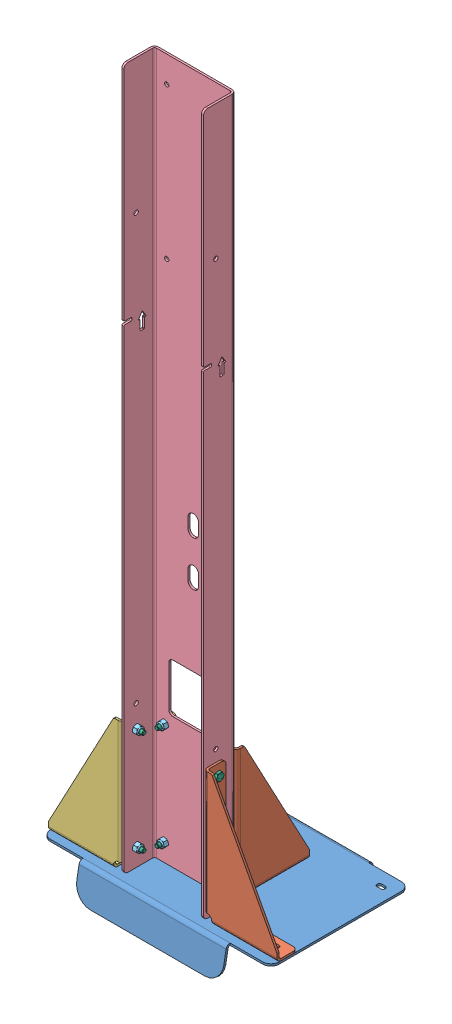
SolidWorks assembly GE-22383, configuration Default. Lengths in mm.
Overall size (355.6 1141.19 244.2).
34 component instances, 6 part files, 31 mates.
Components (placement in the parent):
- GE-22372-1: GE-22372 [Default] at (0 -3.175 0) x (-1 0 0) z (0 0 -1) size (355.6 50.58 244.2)
- GE-22373-1: GE-22373 [Default] at (63.5 3.175 95.25) x (0 1 0) z (0 0 -1) size (203.2 114.3 31.75)
- GE-22373-2: GE-22373 [Default] at (60.325 3.175 47.625) x (0 1 0) z (-1 0 0) size (203.2 114.3 31.75)
- GE-22374-1: GE-22374 [GE-22374] at (-60.325 3.175 47.625) x (0 1 0) z (-1 0 0) size (203.2 114.3 31.75)
- GE-22374-2: GE-22374 [GE-22374] at (-63.5 3.175 95.25) x (0 1 0) z (0 0 1) size (203.2 114.3 31.75)
- GE-22375-1: GE-22375 [Default] at (63.5 1106.4875 98.425) x (-1 0 0) z (0 0 1) size (127 1090.61 50.8)
- nylock_.25_20-2: nylock_.25_20 [Default] at (92.075 0 79.375) x (0.987919 0 -0.154972) z (-0.154972 0 -0.987919) size (11.11 7.94 12.83)
- hex_.25_20_0.75-2: hex_.25_20_0.75 [Default] at (92.075 -1.1906 79.375) x (0 -1 0) z (0.968106 0 -0.250542) size (23.02 12.83 11.11)
- hex_.25_20_0.75-3: hex_.25_20_0.75 [Default] at (59.1344 31.75 79.375) x (-1 0 0) z (0 -0.405813 -0.913956) size (23.02 12.83 11.11)
- hex_.25_20_0.75-4: hex_.25_20_0.75 [Default] at (-44.45 31.75 51.9906) x (0 0 1) z (-0.989795 -0.142496 0) size (23.02 12.83 11.11)
- nylock_.25_20-3: nylock_.25_20 [Default] at (60.325 31.75 79.375) x (0 -0.653939 0.756548) z (0 -0.756548 -0.653939) size (11.11 7.94 12.83)
- nylock_.25_20-4: nylock_.25_20 [Default] at (-44.45 31.75 50.8) x (0.219001 0.975725 0) z (0.975725 -0.219001 0) size (11.11 7.94 12.83)
- nylock_.25_20-5: nylock_.25_20 [Default] at (-92.075 0 79.375) x (0.987919 0 -0.154972) z (-0.154972 0 -0.987919) size (11.11 7.94 12.83)
- nylock_.25_20-6: nylock_.25_20 [Default] at (-44.45 0 -44.45) x (0.987919 0 -0.154972) z (-0.154972 0 -0.987919) size (11.11 7.94 12.83)
- nylock_.25_20-7: nylock_.25_20 [Default] at (44.45 0 -44.45) x (0.987919 0 -0.154972) z (-0.154972 0 -0.987919) size (11.11 7.94 12.83)
- nylock_.25_20-8: nylock_.25_20 [Default] at (-44.45 0 19.05) x (0.987919 0 -0.154972) z (-0.154972 0 -0.987919) size (11.11 7.94 12.83)
- nylock_.25_20-9: nylock_.25_20 [Default] at (44.45 0 19.05) x (0.987919 0 -0.154972) z (-0.154972 0 -0.987919) size (11.11 7.94 12.83)
- hex_.25_20_0.75-5: hex_.25_20_0.75 [Default] at (-92.075 -1.1906 79.375) x (0 -1 0) z (0.968106 0 -0.250542) size (23.02 12.83 11.11)
- hex_.25_20_0.75-6: hex_.25_20_0.75 [Default] at (-44.45 -1.1906 -44.45) x (0 -1 0) z (0.968106 0 -0.250542) size (23.02 12.83 11.11)
- hex_.25_20_0.75-7: hex_.25_20_0.75 [Default] at (44.45 -1.1906 -44.45) x (0 -1 0) z (0.968106 0 -0.250542) size (23.02 12.83 11.11)
- hex_.25_20_0.75-8: hex_.25_20_0.75 [Default] at (-44.45 -1.1906 19.05) x (0 -1 0) z (0.968106 0 -0.250542) size (23.02 12.83 11.11)
- hex_.25_20_0.75-9: hex_.25_20_0.75 [Default] at (44.45 -1.1906 19.05) x (0 -1 0) z (0.968106 0 -0.250542) size (23.02 12.83 11.11)
- nylock_.25_20-10: nylock_.25_20 [Default] at (60.325 190.5 79.375) x (0 -0.653939 0.756548) z (0 -0.756548 -0.653939) size (11.11 7.94 12.83)
- hex_.25_20_0.75-10: hex_.25_20_0.75 [Default] at (59.1344 190.5 79.375) x (-1 0 0) z (0 -0.405813 -0.913956) size (23.02 12.83 11.11)
- hex_.25_20_0.75-12: hex_.25_20_0.75 [Default] at (-59.1344 31.75 79.375) x (1 0 0) z (0 0.750375 0.661012) size (23.02 12.83 11.11)
- nylock_.25_20-12: nylock_.25_20 [Default] at (-60.325 31.75 79.375) x (0 -0.957606 -0.288082) z (0 -0.288082 0.957606) size (11.11 7.94 12.83)
- hex_.25_20_0.75-13: hex_.25_20_0.75 [Default] at (-59.1344 190.5 79.375) x (1 0 0) z (0 0.750375 0.661012) size (23.02 12.83 11.11)
- nylock_.25_20-13: nylock_.25_20 [Default] at (-60.325 190.5 79.375) x (0 -0.957606 -0.288082) z (0 -0.288082 0.957606) size (11.11 7.94 12.83)
- nylock_.25_20-14: nylock_.25_20 [Default] at (-44.45 190.5 50.8) x (0.219001 0.975725 0) z (0.975725 -0.219001 0) size (11.11 7.94 12.83)
- nylock_.25_20-15: nylock_.25_20 [Default] at (44.45 190.5 50.8) x (0.219001 0.975725 0) z (0.975725 -0.219001 0) size (11.11 7.94 12.83)
- nylock_.25_20-16: nylock_.25_20 [Default] at (44.45 31.75 50.8) x (0.219001 0.975725 0) z (0.975725 -0.219001 0) size (11.11 7.94 12.83)
- hex_.25_20_0.75-14: hex_.25_20_0.75 [Default] at (-44.45 190.5 51.9906) x (0 0 1) z (-0.989795 -0.142496 0) size (23.02 12.83 11.11)
- hex_.25_20_0.75-15: hex_.25_20_0.75 [Default] at (44.45 190.5 51.9906) x (0 0 1) z (-0.989795 -0.142496 0) size (23.02 12.83 11.11)
- hex_.25_20_0.75-16: hex_.25_20_0.75 [Default] at (44.45 31.75 51.9906) x (0 0 1) z (-0.989795 -0.142496 0) size (23.02 12.83 11.11)
Mates (geometry in assembly coordinates):
- Concentric64: concentric anti-aligned: cylinder of GE-22375-1 through (-63.5 190.5 79.375) axis (-1 0 0) radius 3.5712; cylinder of GE-22373-1 through (66.675 190.5 79.375) axis (1 0 0) radius 3.3782
- Concentric65: concentric anti-aligned: cylinder of GE-22375-1 through (-63.5 31.75 79.375) axis (-1 0 0) radius 3.5712; cylinder of GE-22373-1 through (66.675 31.75 79.375) axis (1 0 0) radius 3.3782
- Coincident307: coincident anti-aligned: plane of GE-22375-1 through (63.5 3.175 98.425) normal (1 0 0); plane of GE-22373-1 through (63.5 3.175 95.25) normal (-1 0 0)
- Coincident309: coincident anti-aligned: plane of GE-22372-1 through (0 3.175 0) normal (0 1 0); plane of GE-22373-1 through (63.5 3.175 95.25) normal (0 -1 0)
- Concentric74: concentric aligned: cylinder of GE-22372-1 through (92.075 3.175 79.375) axis (0 1 0) radius 3.5712; cylinder of GE-22373-1 through (92.075 6.35 79.375) axis (0 1 0) radius 3.3782
- Concentric66: concentric aligned: cylinder of GE-22375-1 through (44.45 190.5 47.625) axis (0 0 -1) radius 3.5712; cylinder of GE-22373-2 through (44.45 190.5 44.45) axis (0 0 -1) radius 3.3782
- Concentric67: concentric aligned: cylinder of GE-22375-1 through (44.45 31.75 47.625) axis (0 0 -1) radius 3.5712; cylinder of GE-22373-2 through (44.45 31.75 44.45) axis (0 0 -1) radius 3.3782
- Coincident306: coincident anti-aligned: plane of GE-22375-1 through (63.5 3.175 47.625) normal (0 0 -1); plane of GE-22373-2 through (60.325 3.175 47.625) normal (0 0 1)
- Coincident318362: coincident anti-aligned: plane of GE-22372-1 through (0 3.175 0) normal (0 1 0); plane of GE-22374-1 through (-60.325 3.175 47.625) normal (0 -1 0)
- Concentric78262: concentric aligned: cylinder of GE-22375-1 through (-44.45 190.5 47.625) axis (0 0 -1) radius 3.5712; cylinder of GE-22374-1 through (-44.45 190.5 44.45) axis (0 0 -1) radius 3.3782
- Coincident318364: coincident anti-aligned: plane of GE-22375-1 through (63.5 3.175 47.625) normal (0 0 -1); plane of GE-22374-1 through (-60.325 3.175 47.625) normal (0 0 1)
- Concentric75: concentric aligned: cylinder of GE-22372-1 through (-92.075 3.175 79.375) axis (0 1 0) radius 3.5712; cylinder of GE-22374-2 through (-92.075 6.35 79.375) axis (0 1 0) radius 3.3782
- Coincident318363: coincident anti-aligned: plane of GE-22372-1 through (0 3.175 0) normal (0 1 0); plane of GE-22374-2 through (-63.5 3.175 95.25) normal (0 -1 0)
- Concentric78263: concentric aligned: cylinder of GE-22375-1 through (-63.5 190.5 79.375) axis (-1 0 0) radius 3.5712; cylinder of GE-22374-2 through (-66.675 190.5 79.375) axis (-1 0 0) radius 3.3782
- Width1: width anti-aligned: plane of GE-22375-1 through (63.5 3.175 98.425) normal (1 0 0); plane of GE-22372-1 through (-63.5 3.175 47.625) normal (-1 0 0); plane of GE-22375-1 through (-177.8 3.175 -107.95) normal (-1 0 0); plane of GE-22372-1 through (177.8 3.175 -107.95) normal (1 0 0)
- Concentric782641: concentric anti-aligned: cylinder of GE-22372-1 through (92.075 3.175 79.375) axis (0 1 0) radius 3.5712; cylinder of nylock_.25_20-2 through (92.075 0 79.375) axis (0 -1 0) radius 3.175
- Coincident3183651: coincident anti-aligned: plane of GE-22372-1 through (0 0 0) normal (0 -1 0); plane of nylock_.25_20-2 through (92.075 0 79.375) normal (0 1 0)
- Concentric782651: concentric anti-aligned: cylinder of GE-22373-1 through (92.075 6.35 79.375) axis (0 1 0) radius 3.3782; cylinder of hex_.25_20_0.75-2 through (92.075 6.35 79.375) axis (0 -1 0) radius 3.175
- Coincident3183661: coincident anti-aligned: plane of GE-22373-1 through (63.5 6.35 95.25) normal (0 1 0); plane of hex_.25_20_0.75-2 through (96.6503 6.35 74.8773) normal (0 -1 0)
- Concentric782661: concentric anti-aligned: cylinder of GE-22373-1 through (66.675 31.75 79.375) axis (1 0 0) radius 3.3782; cylinder of hex_.25_20_0.75-3 through (66.675 31.75 79.375) axis (-1 0 0) radius 3.175
- Coincident3183671: coincident anti-aligned: plane of GE-22373-1 through (66.675 3.175 95.25) normal (1 0 0); plane of hex_.25_20_0.75-3 through (66.675 32.4271 72.995) normal (-1 0 0)
- Concentric782671: concentric anti-aligned: cylinder of GE-22374-1 through (-44.45 31.75 44.45) axis (0 0 -1) radius 3.3782; cylinder of hex_.25_20_0.75-4 through (-44.45 31.75 44.45) axis (0 0 1) radius 3.175
- Coincident3183681: coincident anti-aligned: plane of GE-22374-1 through (-60.325 3.175 44.45) normal (0 0 -1); plane of hex_.25_20_0.75-4 through (-50.4067 34.1334 44.45) normal (0 0 1)
- Concentric782681: concentric aligned: cylinder of GE-22375-1 through (-63.5 31.75 79.375) axis (-1 0 0) radius 3.5712; cylinder of nylock_.25_20-3 through (60.325 31.75 79.375) axis (-1 0 0) radius 3.175
- Coincident3183691: coincident anti-aligned: plane of GE-22375-1 through (60.325 3.175 98.425) normal (-1 0 0); plane of nylock_.25_20-3 through (60.325 31.75 79.375) normal (1 0 0)
- Concentric782691: concentric anti-aligned: cylinder of GE-22375-1 through (-44.45 31.75 47.625) axis (0 0 -1) radius 3.5712; cylinder of nylock_.25_20-4 through (-44.45 31.75 50.8) axis (0 0 1) radius 3.175
- Coincident3183701: coincident anti-aligned: plane of GE-22375-1 through (63.5 3.175 50.8) normal (0 0 1); plane of nylock_.25_20-4 through (-44.45 31.75 50.8) normal (0 0 -1)
- Concentric782701: concentric anti-aligned: cylinder of GE-22374-2 through (-66.675 31.75 79.375) axis (-1 0 0) radius 3.3782; cylinder of hex_.25_20_0.75-12 through (-66.675 31.75 79.375) axis (1 0 0) radius 3.175
- Coincident3183711: coincident anti-aligned: plane of GE-22374-2 through (-66.675 3.175 95.25) normal (-1 0 0); plane of hex_.25_20_0.75-12 through (-66.675 38.0397 80.6406) normal (1 0 0)
- Concentric782711: concentric anti-aligned: cylinder of GE-22375-1 through (-63.5 31.75 79.375) axis (-1 0 0) radius 3.5712; cylinder of nylock_.25_20-12 through (-60.325 31.75 79.375) axis (1 0 0) radius 3.175
- Coincident3183721: coincident anti-aligned: plane of GE-22375-1 through (-60.325 3.175 47.625) normal (1 0 0); plane of nylock_.25_20-12 through (-60.325 31.75 79.375) normal (-1 0 0)
